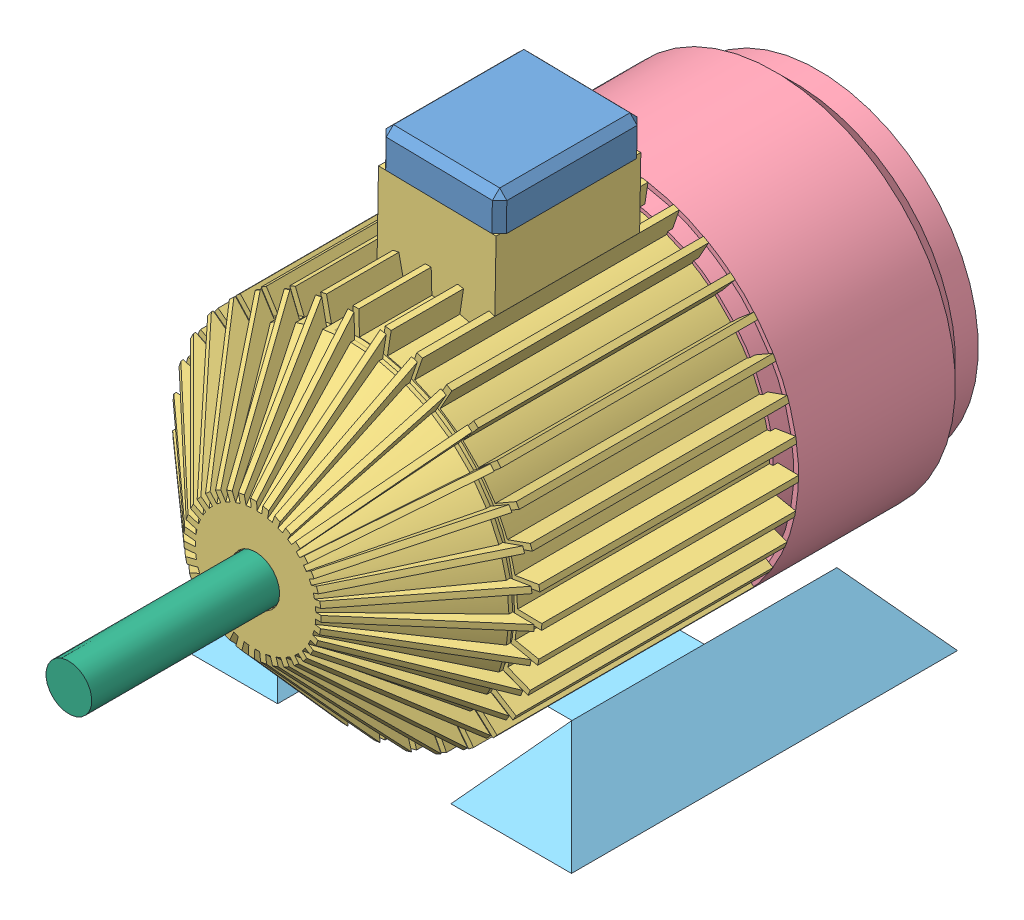
SolidWorks assembly Motor, configuration Default. Lengths in mm.
Overall size (208.1 219.45 312.46).
6 component instances, 6 part files, 11 mates.
Components (placement in the parent):
- Cover-1: Cover [Default] at (144.4848 143.8449 50.1855) x (0.999853 -0.017151 0) z (0 0 1) size (50 15 60)
- Inel-1: Inel [Default] at (142.1623 43.87 13.839) x (0.984312 0.176439 0) z (0.176439 -0.984312 0) size (120 70 120)
- Partea din fata motor-1: Partea din fata motor [Default] at (142.1623 43.87 153.8118) x (0.017151 0.999853 0) z (0.999853 -0.017151 0) size (174.98 170 149.81)
- Partea din spate-1: Partea din spate [Default] at (142.1623 43.87 3.7308) x (0.83088 -0.556452 0) z (0.556452 0.83088 0) size (150 87 150)
- Picior-1: Picior [Default] at (163.0676 -41.13 53.7574) size (171.81 29.79 160)
- Roata-1: Roata [Default] at (142.1623 43.87 31.1954) x (-0.076147 0.997097 0) z (0.997097 0.076147 0) size (60 200 58.75)
Mates (geometry in assembly coordinates):
- Concentric5: concentric aligned: cylinder of Partea din fata motor-1 through (142.1623 43.87 -16.1882) axis (0 0 1) radius 63; cylinder of Picior-1 through (142.1623 43.87 -26.2426) axis (0 0 1) radius 75
- Concentric7: concentric aligned: cylinder of Inel-1 through (142.1623 43.87 83.839) axis (0 0 -1) radius 60; cylinder of Roata-1 through (142.1623 43.87 231.1954) axis (0 0 -1) radius 9.5
- Concentric8: concentric anti-aligned: cylinder of Partea din fata motor-1 through (142.1623 43.87 -16.1882) axis (0 0 1) radius 10; cylinder of Roata-1 through (142.1623 43.87 231.1954) axis (0 0 -1) radius 9.5
- Coincident4: coincident anti-aligned: plane of Cover-1 through (144.4848 143.8449 50.1855) normal (-0.017151 -0.999853 0); plane of Partea din fata motor-1 through (143.8774 143.8553 153.8118) normal (0.017151 0.999853 0)
- Coincident5: coincident aligned: plane of Cover-1 through (119.7457 159.2715 20.1855) normal (-0.999853 0.017151 0); plane of Partea din fata motor-1 through (116.4873 -30.6832 80.1855) normal (-0.999853 0.017151 0)
- Coincident6: coincident aligned: plane of Cover-1 through (119.7457 159.2715 20.1855) normal (0 0 -1); plane of Partea din fata motor-1 through (165.228 -31.5192 20.1855) normal (0 0 -1)
- Coincident7: coincident aligned: plane of Cover-1 through (119.7457 159.2715 20.1855) normal (-0.999853 0.017151 0); plane of Partea din fata motor-1 through (116.4873 -30.6832 80.1855) normal (-0.999853 0.017151 0)
- Coincident9: coincident anti-aligned: plane of Partea din fata motor-1 through (225.4353 41.1914 3.7308) normal (0 0 -1); plane of Partea din spate-1 through (142.1623 43.87 3.7308) normal (0 0 1)
- Concentric10: concentric anti-aligned: cylinder of Partea din fata motor-1 through (142.1623 43.87 -16.1882) axis (0 0 1) radius 65; circle of Partea din spate-1
- Concentric11: concentric anti-aligned: circle of Partea din spate-1; cylinder of Roata-1 through (142.1623 43.87 231.1954) axis (0 0 -1) radius 9.5
- Concentric12: concentric anti-aligned: cylinder of Partea din fata motor-1 through (142.1623 43.87 -16.1882) axis (0 0 1) radius 63; cylinder of Roata-1 through (142.1623 43.87 101.1954) axis (0 0 -1) radius 30
